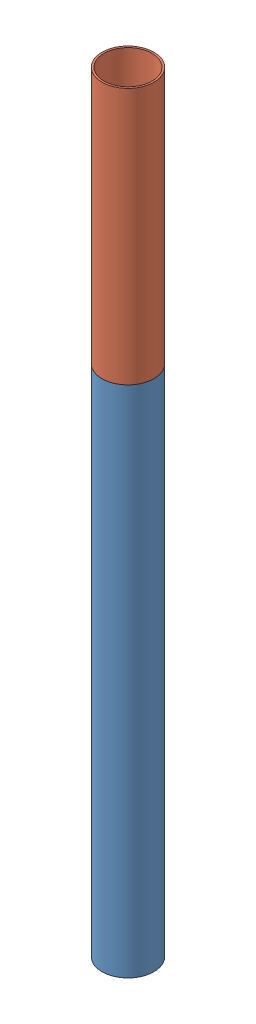
SolidWorks assembly S2_S_Airframe, configuration Default. Lengths in mm.
Overall size (82.2 1219.2 82.2).
2 component instances, 2 part files, 9 mates.
Components (placement in the parent):
- S2_S_Aft_Airframe-1: S2_S_Aft_Airframe [Default] at origin size (82.2 812.8 82.2)
- S2_S_Forward_Airframe-2: S2_S_Forward_Airframe [Default] at (0 812.8 0) size (82.2 406.4 82.2)
Mates (geometry in assembly coordinates):
- Coincident1: coincident aligned: line of S2_S_Forward_Airframe-1 through (335.28 0 1203.96) axis (0 0 1)
- Coincident2: coincident aligned: plane of S2_S_Aft_Airframe-1 through (0 812.8 0) normal (0 1 0); plane of S2_S_Forward_Airframe-1 through (0 1219.2 0) normal (0 1 0)
- Parallel1: parallel anti-aligned: plane of S2_S_Forward_Airframe-1 through (0 1219.2 0) normal (0 0 -1)
- Coincident3: coincident aligned: line of S2_S_Aft_Airframe-1 through (894.08 0 -40.64) axis (0 0 1)
- Coincident4: coincident aligned: plane of S2_S_Aft_Airframe-1 through (0 0 0) normal (0 1 0)
- Parallel2: parallel aligned: plane of S2_S_Aft_Airframe-1 through (0 0 0) normal (0 0 1)
- Parallel3: parallel aligned: plane of S2_S_Forward_Airframe-2 through (0 812.8 0) normal (0 0 1)
- Coincident5: coincident aligned: line of S2_S_Forward_Airframe-2 through (447.04 0 792.48) axis (0 0 1)
- Coincident6: coincident aligned: plane of S2_S_Aft_Airframe-1 through (0 812.8 0) normal (0 1 0); plane of S2_S_Forward_Airframe-2 through (0 812.8 0) normal (0 1 0)
